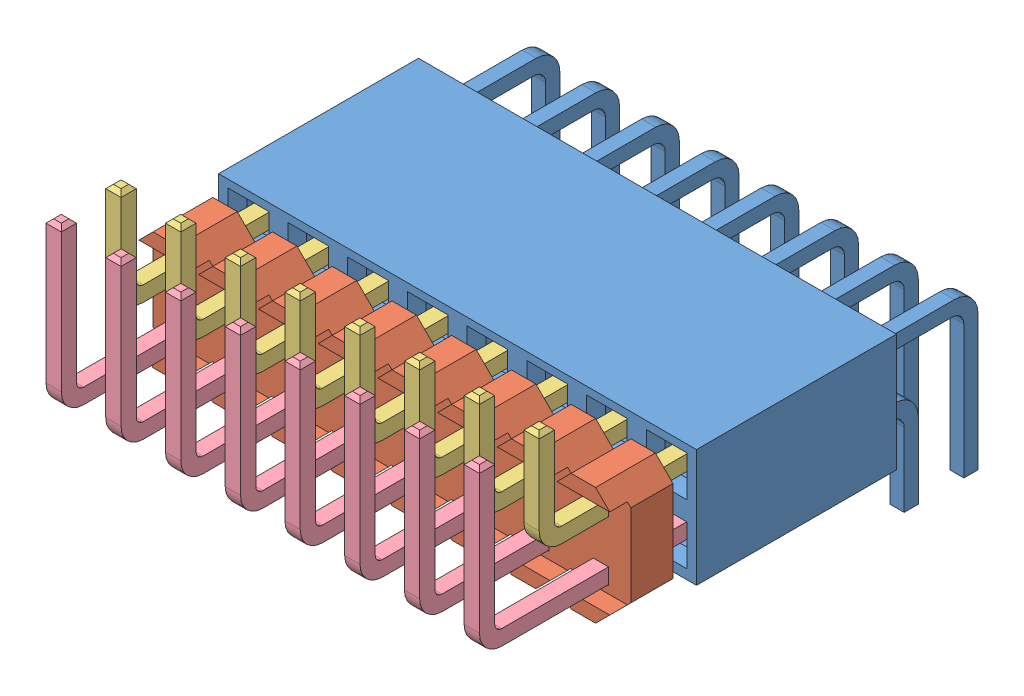
SolidWorks assembly PLS_BLS_16R_ASM, configuration По умолчанию. Lengths in mm.
Overall size (20.32 10.85 21.22).
19 component instances, 4 part files, 3 mates.
Components (placement in the parent):
- PBS_16R-1: PBS_16R [По умолчанию] at origin size (20.32 7.9 12.94)
- PLD-16R-2: PLD-16R [Default] at (9.21 5.45 5.74) x (0 0 -1) z (0 -1 0) size (13.04 20.32 7.95)
  - PLD-16 plastic-1: PLD-16 plastic [Default] at (2.2 -0.32 5.45) x (0 -1 0) z (1 0 0) size (20.32 5 2.54)
  - PLD-R-PIN-1: PLD-R-PIN [Default] x (1 0 0) z (0 -1 0) size (10.5 4.5 0.65)
  - PLD-R-PIN-2: PLD-R-PIN [Default] at (0 -2.54 0) x (1 0 0) z (0 -1 0) size (10.5 4.5 0.65)
  - PLD-R-PIN-3: PLD-R-PIN [Default] at (0 -5.08 0) x (1 0 0) z (0 -1 0) size (10.5 4.5 0.65)
  - PLD-R-PIN-4: PLD-R-PIN [Default] at (0 -7.62 0) x (1 0 0) z (0 -1 0) size (10.5 4.5 0.65)
  - PLD-R-PIN-5: PLD-R-PIN [Default] at (0 -10.16 0) x (1 0 0) z (0 -1 0) size (10.5 4.5 0.65)
  - PLD-R-PIN-6: PLD-R-PIN [Default] at (0 -12.7 0) x (1 0 0) z (0 -1 0) size (10.5 4.5 0.65)
  - PLD-R-PIN-7: PLD-R-PIN [Default] at (0 -15.24 0) x (1 0 0) z (0 -1 0) size (10.5 4.5 0.65)
  - PLD-R-PIN-8: PLD-R-PIN [Default] at (0 -17.78 0) x (1 0 0) z (0 -1 0) size (10.5 4.5 0.65)
  - PLD_R_PIN_BIG-1: PLD_R_PIN_BIG [Default] at (-2.54 0 0) x (1 0 0) z (0 -1 0) size (13 7 0.65)
  - PLD_R_PIN_BIG-2: PLD_R_PIN_BIG [Default] at (-2.54 -2.54 0) x (1 0 0) z (0 -1 0) size (13 7 0.65)
  - PLD_R_PIN_BIG-3: PLD_R_PIN_BIG [Default] at (-2.54 -5.08 0) x (1 0 0) z (0 -1 0) size (13 7 0.65)
  - PLD_R_PIN_BIG-4: PLD_R_PIN_BIG [Default] at (-2.54 -7.62 0) x (1 0 0) z (0 -1 0) size (13 7 0.65)
  - PLD_R_PIN_BIG-5: PLD_R_PIN_BIG [Default] at (-2.54 -10.16 0) x (1 0 0) z (0 -1 0) size (13 7 0.65)
  - PLD_R_PIN_BIG-6: PLD_R_PIN_BIG [Default] at (-2.54 -12.7 0) x (1 0 0) z (0 -1 0) size (13 7 0.65)
  - PLD_R_PIN_BIG-7: PLD_R_PIN_BIG [Default] at (-2.54 -15.24 0) x (1 0 0) z (0 -1 0) size (13 7 0.65)
  - PLD_R_PIN_BIG-8: PLD_R_PIN_BIG [Default] at (-2.54 -17.78 0) x (1 0 0) z (0 -1 0) size (13 7 0.65)
Mates (geometry in assembly coordinates):
- Совпадение1: coincident aligned: plane of PBS_16R-1 through (-10.16 -2.5 -8.5) normal (0 -1 0); plane of PLD-16R-2/PLD-16 plastic-1 through (9.41 -2.5 0) normal (0 -1 0)
- Совпадение2: coincident aligned: plane of PBS_16R-1 through (-10.16 2.5 -8.5) normal (-1 0 0); plane of PLD-16R-2/PLD-16 plastic-1 through (-10.16 1.75 0) normal (-1 0 0)
- Расстояние1: distance = 1 mm anti-aligned: plane of PBS_16R-1 through (0 0 0) normal (0 0 1); plane of PLD-16R-2/PLD-16 plastic-1 through (10.16 2.5 1) normal (0 0 -1)
